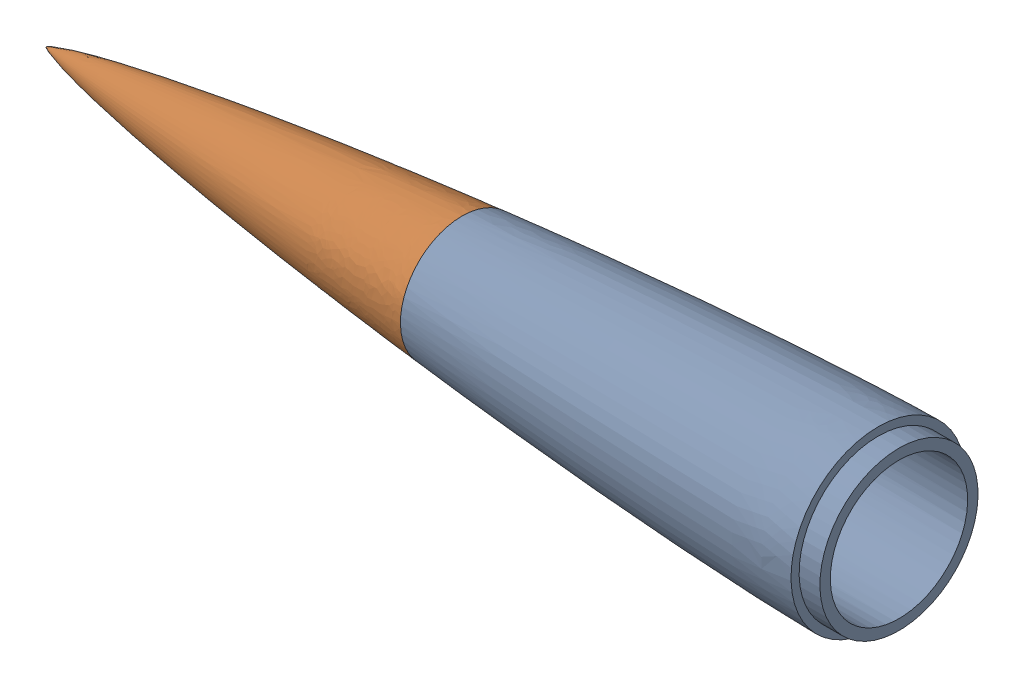
SolidWorks assembly Nose Cone Assembly, configuration Default. Lengths in mm.
Overall size (410 83.8 83.8).
2 component instances, 2 part files, 3 mates.
Components (placement in the parent):
- Jefff Nose Cone bottom-1: Jefff Nose Cone bottom [Default] at origin size (211.44 83.8 83.8)
- Jefff Nose Cone Top-1: Jefff Nose Cone Top [Default] at (50 0 0) size (215.05 59.26 59.26)
Mates (geometry in assembly coordinates):
- Coincident1: coordinate: point of Jefff Nose Cone bottom-1
- Coincident2: coincident anti-aligned: plane of Jefff Nose Cone bottom-1 through (-210 0 0) normal (-1 0 0); plane of Jefff Nose Cone Top-1 through (-210 0 0) normal (1 0 0)
- Coincident3: coincident aligned: circle of Jefff Nose Cone bottom-1; circle of Jefff Nose Cone Top-1
